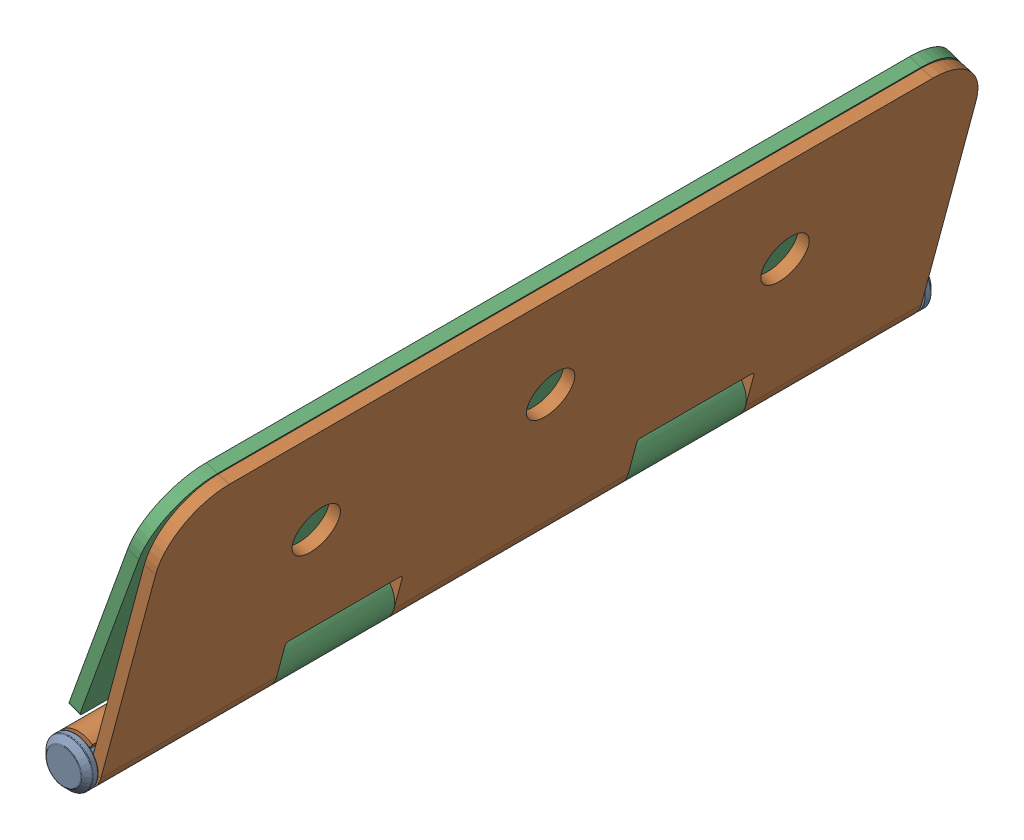
SolidWorks assembly Hinge Assembly, configuration Default. Lengths in mm.
Overall size (61.29 126.46 362.5).
3 component instances, 3 part files, 4 mates.
Components (placement in the parent):
- Pin for Door-1: Pin for Door [Default] at origin size (20 20 362.5)
- Door Hinge-1: Door Hinge [Default] at (21.0446 56.9169 35.0125) x (0 0 -1) z (-0.96574 0.259512 0) size (350 125 20)
- Door Hinge Part 2-1: Door Hinge Part 2 [Default] at (17.1225 65.9405 -34.9875) x (0 0 1) z (0.940497 -0.339802 0) size (350 125 20)
Mates (geometry in assembly coordinates):
- Concentric2: concentric anti-aligned: cylinder of Pin for Door-1 through (0 0 176.2625) axis (0 0 -1) radius 4.625; cylinder of Door Hinge-1 through (0 0 50.0125) axis (0 0 1) radius 5
- Width1: width aligned: plane of Pin for Door-1 through (0 0 176.2625) normal (0 0 -1); plane of Pin for Door-1 through (0 0 -176.2375) normal (0 0 1); plane of Door Hinge-1 through (7.0623 -12.2525 -174.9875) normal (0 0 -1); plane of Door Hinge-1 through (39.5013 108.4649 175.0125) normal (0 0 1)
- Hinge1: hinge anti-aligned: cylinder of Door Hinge Part 2-1 through (0 0 50.0125) axis (0 0 -1) radius 5; cylinder of Door Hinge-1 through (0 0 50.0125) axis (0 0 1) radius 5; plane of Door Hinge Part 2-1 through (0 0 -99.9875) normal (0 0 -1); plane of Door Hinge-1 through (0 0 -99.9875) normal (0 0 1)
- LimitAngle2: limit planar angle = 0.084189 rad anti-aligned: plane of Door Hinge Part 2-1 through (34.3747 109.8562 -174.9875) normal (0.940497 -0.339802 0); plane of Door Hinge-1 through (34.6726 109.7625 175.0125) normal (-0.96574 0.259512 0)
